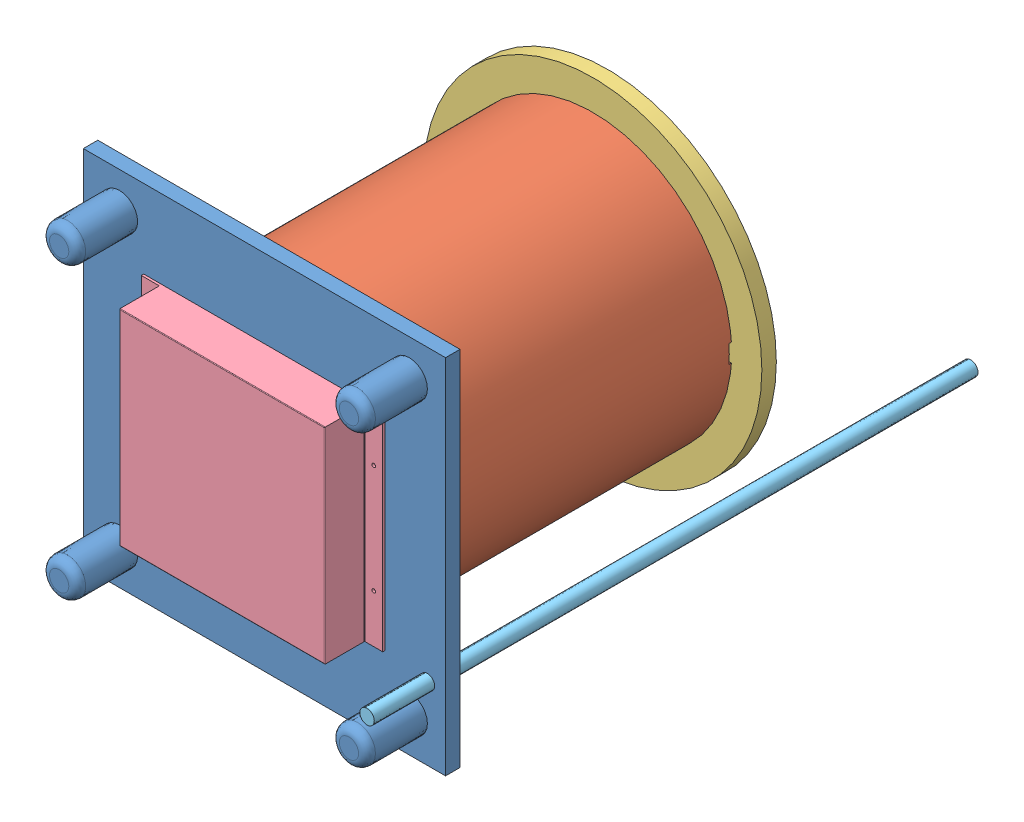
SolidWorks assembly Assembly Prototype, configuration Default. Lengths in mm.
Overall size (300 300 500).
5 component instances, 5 part files, 13 mates.
Components (placement in the parent):
- Bottom plate-1: Bottom plate [Default] at origin size (300 300 62)
- Reservoir-1: Reservoir [Default] at (0 0 -260) x (-1 0 0) z (0 0 1) size (230 230 260)
- Top-1: Top [Default] at (0 0 -260) x (-1 0 0) z (0 0 -1) size (280 280 12)
- Bottom box-2: Bottom box [Default] at (0 0 47) x (-1 0 0) z (0 0 -1) size (200 170 35)
- Motor support-1: Motor support [Default] at (135 -90 -438) size (12 12 500)
Mates (geometry in assembly coordinates):
- Coincident2: coincident anti-aligned: plane of Reservoir-1 through (0 0 -260) normal (0 0 -1); plane of Top-1 through (0 0 -260) normal (0 0 1)
- Coincident3: coincident anti-aligned: plane of Reservoir-1; plane of assembly through (0 0 0) normal (1 0 0)
- Coincident4: coincident anti-aligned: plane of Reservoir-1; plane of assembly through (0 0 0) normal (0 1 0)
- Coincident9: coincident aligned: plane of Top-1; plane of assembly through (0 0 0) normal (0 1 0)
- Coincident10: coincident anti-aligned: plane of Top-1 through (0 0 -260) normal (-1 0 0); plane of assembly through (0 0 0) normal (1 0 0)
- Coincident11: coincident anti-aligned: plane of Bottom plate-1 through (150 -150 12) normal (0 0 1); plane of Bottom box-2 through (-85 85 12) normal (0 0 -1)
- Coincident12: coincident aligned: plane of Bottom box-2; plane of assembly through (0 0 0) normal (0 1 0)
- Coincident13: coincident anti-aligned: plane of Bottom box-2 through (0 0 47) normal (-1 0 0); plane of assembly through (0 0 0) normal (1 0 0)
- Coincident14: coincident anti-aligned: plane of Bottom plate-1 through (150 -150 0) normal (0 0 -1); plane of Reservoir-1 through (0 0 0) normal (0 0 1)
- Concentric1: concentric anti-aligned: cylinder of Bottom plate-1 through (135 -90 12) axis (0 0 1) radius 6; cylinder of Motor support-1 through (135 -90 62) axis (0 0 -1) radius 6
- Distance1: distance = 50 mm aligned: plane of Motor support-1 through (135 -90 62) normal (0 0 1); plane of Bottom plate-1 through (150 -150 12) normal (0 0 1)
- Axis2: unknown: cylinder of Bottom plate-1 through (135 -90 12) axis (0 0 1) radius 6
- Axis3: unknown: cylinder of Motor support-1 through (283.552 267.9735 192.1212) axis (0 0 -1) radius 6
